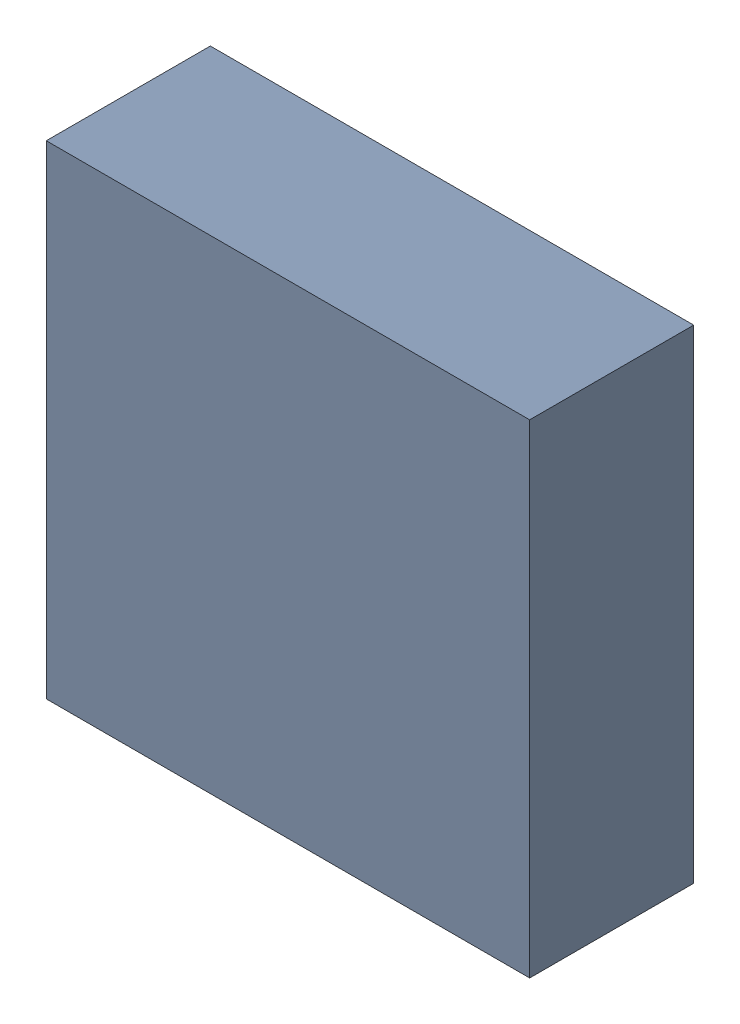
SolidWorks assembly U25, configuration ﾃﾞﾌｫﾙﾄ. Lengths in mm.
Overall size (3.3 3.3 1.12).
2 component instances, 1 part files, 0 mates.
Components (placement in the parent):
- 689263008-1: 689263008 [ﾃﾞﾌｫﾙﾄ] at (23 51 0) size (3.3 3.3 1.12)
  - Extruded_44-1: Extruded_44 [ﾃﾞﾌｫﾙﾄ] at origin size (3.3 3.3 1.12)
